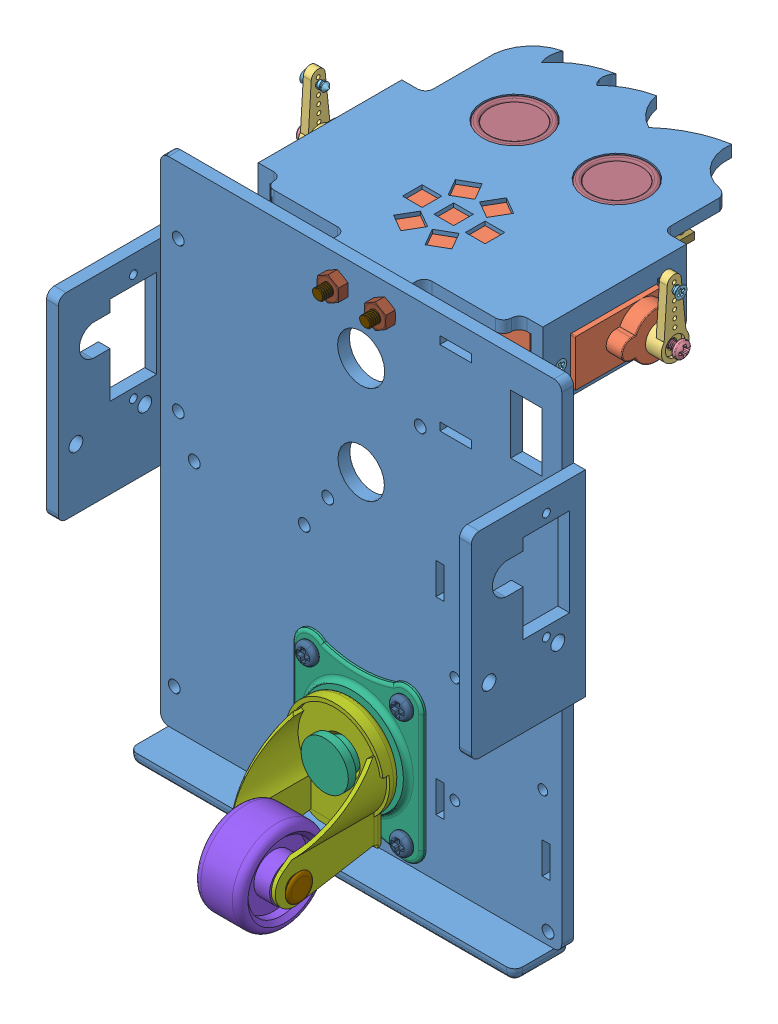
SolidWorks assembly DYOR_3D_LS_AR, configuration Predeterminado. Lengths in mm.
Overall size (108 136.43 112.97).
50 component instances, 20 part files, 21 mates.
Components (placement in the parent):
- Base-1: Base [Predeterminado] at (60.418 -80.9125 12.5389) size (108 128.45 29)
- AR1-1: AR1 [Predeterminado] at (-132.1681 230.6023 -125.9386) size (34.06 21.84 31.9)
  - sg90-2: sg90 [Default] at (126.818 -193.0635 98.9775) x (0 0 1) z (0 -1 0) size (31.9 29.9 11.8)
  - SG90 plastic Horn-2: SG90 plastic Horn [Default] at (97.368 -198.9635 104.8775) x (0 0.999767 0.021606) z (0 -0.021606 0.999767) size (19.4 4 7.07)
  - (M2_3_mm)_90116A007_METRIC 316 SS PAN HEAD PHILLIPS MACHINE SCREW-2: (M2_3_mm)_90116A007_METRIC 316 SS PAN HEAD PHILLIPS MACHINE SCREW [90116A007] at (97.368 -198.9635 104.8775) x (0 0 1) z (-1 0 0) size (4 4 4.68)
  - M2x6 SelfTap Screw-1: M2x6 SelfTap Screw [Predeterminado] at (93.868 -186.4635 104.8775) x (0 0.924225 0.381849) z (-1 0 0) size (3.4 3.28 6)
  - M2x6 SelfTap Screw-3: M2x6 SelfTap Screw [Predeterminado] at (105.418 -198.9635 123.8775) x (0 0.924225 0.381849) z (-1 0 0) size (3.4 3.28 6)
  - M2x6 SelfTap Screw-5: M2x6 SelfTap Screw [Predeterminado] at (105.418 -198.9635 96.5775) x (0 0.924225 0.381849) z (-1 0 0) size (3.4 3.28 6)
- AR2-1: AR2 [Predeterminado] at (-151.1865 230.6023 -125.9386) size (34.06 21.82 31.9)
  - sg90-1: sg90 [Default] at (175.3764 -204.8635 98.9775) x (0 0 1) z (0 1 0) size (31.9 29.9 11.8)
  - SG90 plastic Horn-1: SG90 plastic Horn [Default] at (204.8264 -198.9635 104.8775) x (0 0.999858 0.016879) z (0 0.016879 -0.999858) size (19.4 4 7.07)
  - (M2_3_mm)_90116A007_METRIC 316 SS PAN HEAD PHILLIPS MACHINE SCREW-1: (M2_3_mm)_90116A007_METRIC 316 SS PAN HEAD PHILLIPS MACHINE SCREW [90116A007] at (204.8264 -198.9635 104.8775) x (0 0 -1) z (1 0 0) size (4 4 4.68)
  - M2x6 SelfTap Screw-2: M2x6 SelfTap Screw [Predeterminado] at (208.3264 -186.4635 104.8775) x (0 -0.924225 -0.381849) z (1 0 0) size (3.4 3.28 6)
  - M2x6 SelfTap Screw-4: M2x6 SelfTap Screw [Predeterminado] at (196.7764 -198.9635 123.8775) x (0 -0.924225 -0.381849) z (1 0 0) size (3.4 3.28 6)
  - M2x6 SelfTap Screw-6: M2x6 SelfTap Screw [Predeterminado] at (196.7764 -198.9635 96.5775) x (0 -0.924225 -0.381849) z (1 0 0) size (3.4 3.28 6)
- CA-1: CA [Predeterminado] at (-2.207 18.0036 0) size (33 45.94 43.2)
  - Caster Wheel-1: Caster Wheel [Default] at (57.6387 -78.841 57.7572) x (0 1 0) z (-1 0 0) size (45.94 37.59 33)
    - caster holder-1: caster holder [Default] at (-24.0751 44.7184 29.5137) x (1 0 0) z (0 0 -1) size (39 9.27 33)
    - holder-1: holder [Default] at (-1.5751 42.9484 46.0137) x (0 0 1) z (1 0 0) size (25 28.07 31.31)
    - caster wheel-1: caster wheel [Default] at (-15.6961 19.9484 46.0137) x (0.997275 0.073773 0) z (0 0 1) size (23 23 14)
    - Part4-1: Part4 [Default] at (-15.6961 19.9484 55.0137) x (-0.978448 0.206495 0) z (0 0 -1) size (7 7 20)
  - M3x6 Philips Screw-1: M3x6 Philips Screw [Predeterminado] at (23.625 -65.4161 13.5389) size (5.3 5.3 7.81)
  - M3x6 Philips Screw-2: M3x6 Philips Screw [Predeterminado] at (-0.375 -65.4161 13.5389) size (5.3 5.3 7.81)
  - M3x6 Philips Screw-3: M3x6 Philips Screw [Predeterminado] at (-0.375 -95.4161 13.5389) size (5.3 5.3 7.81)
  - M3x6 Philips Screw-4: M3x6 Philips Screw [Predeterminado] at (23.625 -95.4161 13.5389) size (5.3 5.3 7.81)
  - M3 Nut-1: M3 Nut [Predeterminado] at (23.625 -65.4161 11.0389) size (6.27 6.27 2.71)
  - M3 Nut-2: M3 Nut [Predeterminado] at (-0.375 -65.4161 11.0389) size (6.27 6.27 2.71)
  - M3 Nut-3: M3 Nut [Predeterminado] at (-0.375 -95.4161 11.0389) size (6.27 6.27 2.71)
  - M3 Nut-4: M3 Nut [Predeterminado] at (23.625 -95.4161 11.0389) size (6.27 6.27 2.71)
- HC-SR04 Ping Sensor-1: HC-SR04 Ping Sensor [Default] at (9.418 28.7888 -39.4611) x (0 0 -1) z (0 1 0) size (25.18 45 18.07)
  - PCB-1: PCB [Default] at origin size (20.5 45 1.75)
  - Transducer-1: Transducer [Default] at (0 -13 13.25) x (1 0 0) z (0 -1 0) size (15.88 12 15.88)
  - Transducer-2: Transducer [Default] at (0 13 13.25) x (1 0 0) z (0 -1 0) size (15.88 12 15.88)
  - 3 Pin Header 90 Degree-1: 3 Pin Header 90 Degree [Default] at (8.4275 0 -1.25) x (-1 0 0) z (0 -1 0) size (8 7.82 10)
  - 14 Pin SMT-1: 14 Pin SMT [Default] at (-0.35 -18.5 -0.85) x (0 -1 0) z (1 0 0) size (6 1.6 8.8)
  - 14 Pin SMT-2: 14 Pin SMT [Default] at (0 -0.3826 -0.85) x (1 0 0) z (0 1 0) size (6 1.6 8.8)
  - 14 Pin SMT-3: 14 Pin SMT [Default] at (0 17.5274 -0.85) x (1 0 0) z (0 1 0) size (6 1.6 8.8)
  - Cap1 SMT-1: Cap1 SMT [Default] at (-1.755 7.4774 -0.9689) x (0 1 0) z (-1 0 0) size (4.5 1.84 1.75)
  - Cap1 SMT-2: Cap1 SMT [Default] at (6.835 7.4774 -0.9689) x (0 1 0) z (-1 0 0) size (4.5 1.84 1.75)
  - Cap1 SMT-3: Cap1 SMT [Default] at (-6.835 7.4774 -0.9689) x (0 1 0) z (-1 0 0) size (4.5 1.84 1.75)
  - Cap1 SMT-4: Cap1 SMT [Default] at (4.295 7.4774 -0.9689) x (0 1 0) z (-1 0 0) size (4.5 1.84 1.75)
  - Cap1 SMT-5: Cap1 SMT [Default] at (1.755 7.4774 -0.9689) x (0 1 0) z (-1 0 0) size (4.5 1.84 1.75)
  - Cap1 SMT-6: Cap1 SMT [Default] at (-4.295 7.4774 -0.9689) x (0 1 0) z (-1 0 0) size (4.5 1.84 1.75)
  - HC-SR04 Crystal-1: HC-SR04 Crystal [Default] at (-8.3 0 1.75) x (0 -1 0) z (0 0 1) size (10 3.5 2.7)
- M3x10 Philips Screw-1: M3x10 Philips Screw [Predeterminado] at (3.418 36.0388 7.5389) x (-0.459458 -0.8882 0) z (0 0 -1) size (5.3 5.3 11.8)
- M3x10 Philips Screw-2: M3x10 Philips Screw [Predeterminado] at (15.418 36.0388 7.5389) x (-0.386504 -0.922288 0) z (0 0 -1) size (5.3 5.3 11.8)
- M3 Nut-1: M3 Nut [Predeterminado] at (15.418 36.0388 16.5389) size (6.27 6.27 2.71)
- M3 Nut-2: M3 Nut [Predeterminado] at (3.418 36.0388 16.5389) size (6.27 6.27 2.71)
- Front_LS_AR-1: Front_LS_AR [Predeterminado] at (-51.2809 39.5388 -46.4821) x (1 0 0) z (0 1 0) size (72.34 72.38 18.8)
- ws8212-7-1: ws8212-7 [Predeterminado] at (9.418 38.5388 -10.9611) x (0 0 -1) z (0 1 0) size (24 24 3.1)
Mates (geometry in assembly coordinates):
- Coincidente23: coincident: plane of Base-1 through (-39.582 40.5388 12.5389) normal (0 0 1); plane of CA-1/Caster Wheel-1/caster holder-1 through (9.418 -17.6143 12.5389) normal (0 0 -1)
- Concéntrica1: concentric: circle of Base-1; circle of CA-1/Caster Wheel-1/caster holder-1
- Concéntrica2: concentric: circle of Base-1; circle of CA-1/Caster Wheel-1/caster holder-1
- Coincidente30: coincident: plane of Base-1 through (-39.582 40.5388 12.5389) normal (0 0 1); plane of M3 Nut-1 through (15.418 36.0388 12.5389) normal (0 0 -1)
- Coincidente31: coincident: plane of Base-1 through (-39.582 40.5388 12.5389) normal (0 0 1); plane of M3 Nut-2 through (3.418 36.0388 12.5389) normal (0 0 -1)
- Concéntrica7: concentric: circle of Base-1; circle of M3 Nut-1
- Concéntrica8: concentric: circle of Base-1; circle of M3 Nut-2
- Coincidente32: coincident: plane of Base-1 through (-39.582 40.5388 9.5389) normal (0 0 -1); plane of Front_LS_AR-1 through (-0.582 42.5388 9.5389) normal (0 0 1)
- Concéntrica9: concentric: circle of Base-1; circle of Front_LS_AR-1
- Paralelo1: parallel: plane of Base-1 through (-39.582 42.5388 9.5389) normal (0 1 0); plane of Front_LS_AR-1 through (-22.7538 42.5388 -35.9611) normal (0 1 0)
- Concéntrica10: concentric: circle of HC-SR04 Ping Sensor-1/Transducer-1; circle of Front_LS_AR-1
- Concéntrica11: concentric: circle of HC-SR04 Ping Sensor-1/Transducer-2; circle of Front_LS_AR-1
- Coincidente34: coincident: plane of HC-SR04 Ping Sensor-1/Transducer-1 through (22.418 42.5388 -47.4011) normal (0 1 0); plane of Front_LS_AR-1 through (-22.7538 42.5388 -35.9611) normal (0 1 0)
- Coincidente35: coincident: plane of AR2-1/sg90-1 through (24.1899 37.5388 -4.4611) normal (0 0 1); plane of Front_LS_AR-1 through (42.5899 37.5388 -4.4611) normal (0 0 -1)
- Coincidente36: coincident: plane of AR2-1/sg90-1 through (42.5899 25.7388 -31.6611) normal (1 0 0); plane of Front_LS_AR-1 through (42.5899 23.7388 -33.9611) normal (-1 0 0)
- Coincidente37: coincident: plane of AR1-1/sg90-2 through (-5.3501 25.7388 -4.4611) normal (0 0 1); plane of Front_LS_AR-1 through (-23.7501 37.5388 -4.4611) normal (0 0 -1)
- Coincidente38: coincident: plane of AR1-1/sg90-2 through (-5.3501 25.7388 -26.9611) normal (0 -1 0); plane of Front_LS_AR-1 through (-23.7501 25.7388 -4.4611) normal (0 1 0)
- Coincidente39: coincident: plane of AR1-1/sg90-2 through (-23.7501 37.5388 -31.6611) normal (-1 0 0); plane of Front_LS_AR-1 through (-23.7501 23.7388 -33.9611) normal (1 0 0)
- Coincidente40: coincident: plane of Front_LS_AR-1 through (3.918 42.5388 -13.4611) normal (0 0 1); plane of ws8212-7-1 through (-1.082 42.5388 -13.4611) normal (0 0 -1)
- Coincidente41: coincident: plane of Front_LS_AR-1 through (3.918 42.5388 -8.4611) normal (-1 0 0); plane of ws8212-7-1 through (3.918 42.5388 -13.4611) normal (1 0 0)
- Distancia1: distance = 1 mm: plane of Front_LS_AR-1 through (-22.7538 42.5388 -35.9611) normal (0 1 0); plane of ws8212-7-1 through (9.418 41.5388 -10.9611) normal (0 1 0)
